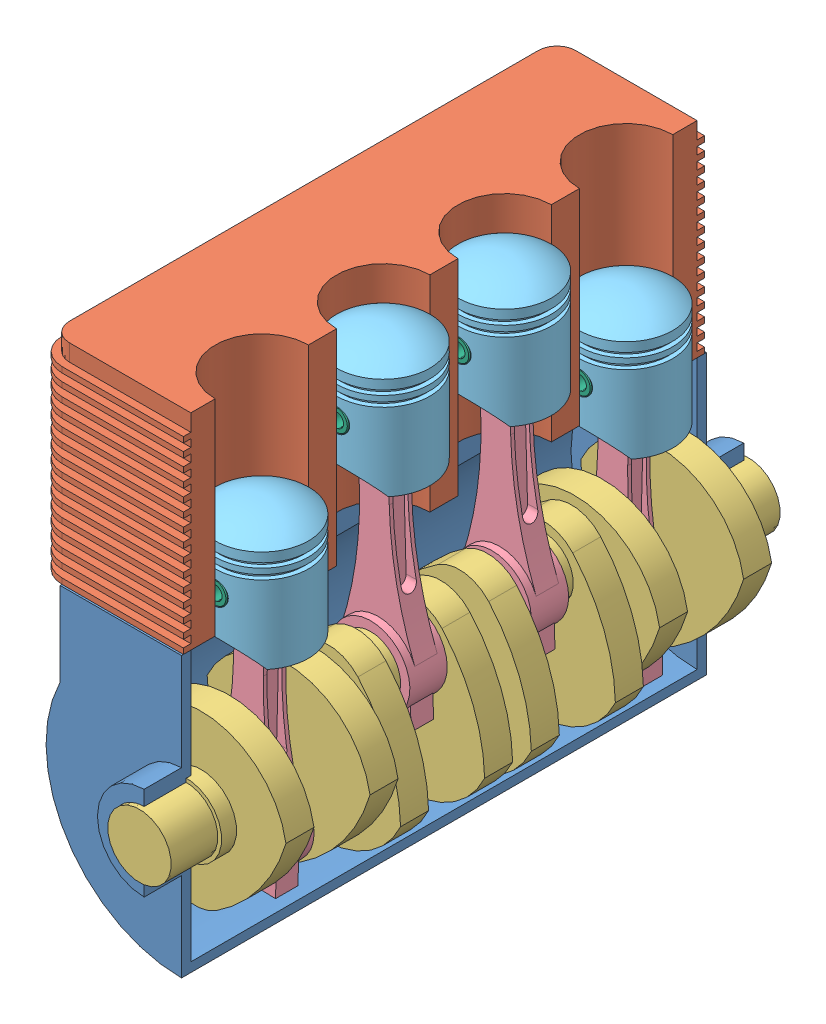
SolidWorks assembly Engine Block, configuration Default. Lengths in mm.
Overall size (128.7 259.5 326).
15 component instances, 6 part files, 29 mates.
Components (placement in the parent):
- Lower Block-1: Lower Block [Default] at (152.1459 172.8222 383.832) size (72.5 149.5 321)
- Upper Block-1: Upper Block [Default] at (114.6459 249.8222 243.332) x (0 0 -1) z (1 0 0) size (279 110 79)
- Crankshaft-1: Crankshaft [Default] at (152.1459 172.8222 381.332) x (0 0 -1) z (-0.991426 0.130668 0) size (326 92 88.14)
- Connecting Rod-1: Connecting Rod [Default] at (149.1155 150.0227 340.832) x (0.999681 -0.025253 0) z (0 0 1) size (42 160.15 20)
- Piston-1: Piston [Default] at (152.1459 239.4844 340.832) size (50 64.17 50)
- Piston Pin-1: Piston Pin [Default] at (152.1459 269.9844 340.832) size (12.5 12.5 50)
- Piston-2: Piston [Default] at (152.1459 239.4844 145.832) x (-1 0 0) z (0 0 -1) size (50 64.17 50)
- Piston Pin-2: Piston Pin [Default] at (152.1459 269.9844 145.832) x (-0.173648 0.984808 0) z (0 0 -1) size (12.5 12.5 50)
- Connecting Rod-2: Connecting Rod [Default] at (149.1155 150.0227 145.832) x (-0.999681 0.025253 0) z (0 0 -1) size (42 160.15 20)
- Connecting Rod-4: Connecting Rod [Default] at (155.4126 197.6078 275.832) x (0.999629 0.027222 0) z (0 0 1) size (42 160.15 20)
- Piston-4: Piston [Default] at (152.1459 287.0634 275.832) size (50 64.17 50)
- Piston Pin-4: Piston Pin [Default] at (152.1459 317.5634 275.832) size (12.5 12.5 50)
- Piston-7: Piston [Default] at (152.1459 287.0634 210.832) x (-1 0 0) z (0 0 -1) size (50 64.17 50)
- Connecting Rod-6: Connecting Rod [Default] at (155.4126 197.6078 210.832) x (-0.999629 -0.027222 0) z (0 0 -1) size (42 160.15 20)
- Piston Pin-6: Piston Pin [Default] at (152.1459 317.5634 210.832) x (-0.173648 0.984808 0) z (0 0 -1) size (12.5 12.5 50)
Mates (geometry in assembly coordinates):
- Coincident4: coincident: plane of Lower Block-1 through (152.1459 197.8222 378.832) normal (1 0 0); plane of Upper Block-1 through (152.1459 359.8222 378.832) normal (1 0 0)
- Coincident5: coincident: plane of Lower Block-1 through (152.1459 249.8222 378.832) normal (0 1 0); plane of Upper Block-1 through (87.1459 249.8222 368.832) normal (0 -1 0)
- Concentric1: concentric: cylinder of Lower Block-1 through (152.1459 172.8222 378.832) axis (0 0 1) radius 17; cylinder of Crankshaft-1 through (152.1459 172.8222 406.332) axis (0 0 -1) radius 17
- Concentric2: concentric: cylinder of Piston-1 through (152.1459 269.9844 315.832) axis (0 0 1) radius 6.25; cylinder of Piston Pin-1 through (152.1459 269.9844 365.832) axis (0 0 -1) radius 6.25
- Tangent1: tangent: cylinder of Piston-1 through (152.1459 301.9844 340.832) axis (0 1 0) radius 25; plane of Piston Pin-1 through (152.1459 269.9844 365.832) normal (0 0 1)
- Width2: width: plane of Piston-1 through (152.1459 269.9844 352.832) normal (0 0 -1); plane of Piston-1 through (152.1459 269.9844 328.832) normal (0 0 1); plane of Connecting Rod-1 through (149.1155 150.0227 350.832) normal (0 0 1); plane of Connecting Rod-1 through (149.1155 150.0227 330.832) normal (0 0 -1)
- Width4: width: plane of Lower Block-1 through (152.1459 172.8222 383.832) normal (0 0 1); plane of Lower Block-1 through (152.1459 172.8222 102.832) normal (0 0 -1); plane of Upper Block-1 through (152.1459 359.8222 107.832) normal (0 0 -1); plane of Upper Block-1 through (152.1459 359.8222 378.832) normal (0 0 1)
- Width5: width: plane of Crankshaft-1 through (152.1459 172.8222 406.332) normal (0 0 1); plane of Crankshaft-1 through (152.1459 172.8222 80.332) normal (0 0 -1); plane of Lower Block-1 through (152.1459 172.8222 82.832) normal (0 0 -1); plane of Lower Block-1 through (152.1459 172.8222 403.832) normal (0 0 1)
- Concentric5: concentric: cylinder of Connecting Rod-1 through (152.1459 269.9844 350.832) axis (0 0 -1) radius 6.25; cylinder of Piston Pin-1 through (152.1459 269.9844 365.832) axis (0 0 -1) radius 6.25
- Concentric6: concentric: cylinder of Crankshaft-1 through (149.1155 150.0227 343.332) axis (0 0 1) radius 16; cylinder of Connecting Rod-1 through (149.1155 150.0227 350.832) axis (0 0 -1) radius 16
- Concentric7: concentric: cylinder of Upper Block-1 through (152.1459 359.8222 340.832) axis (0 -1 0) radius 25; cylinder of Piston-1 through (152.1459 301.9844 340.832) axis (0 1 0) radius 25
- Concentric8: concentric: cylinder of Piston-2 through (152.1459 269.9844 170.832) axis (0 0 -1) radius 6.25; cylinder of Piston Pin-2 through (152.1459 269.9844 120.832) axis (0 0 1) radius 6.25
- Tangent4: tangent: cylinder of Piston-2 through (152.1459 301.9844 145.832) axis (0 1 0) radius 25; plane of Piston Pin-2 through (152.1459 269.9844 120.832) normal (0 0 -1)
- Width6: width: plane of Piston-2 through (152.1459 269.9844 133.832) normal (0 0 1); plane of Piston-2 through (152.1459 269.9844 157.832) normal (0 0 -1); plane of Connecting Rod-2 through (149.1155 150.0227 135.832) normal (0 0 -1); plane of Connecting Rod-2 through (149.1155 150.0227 155.832) normal (0 0 1)
- Concentric9: concentric: cylinder of Piston Pin-2 through (152.1459 269.9844 120.832) axis (0 0 1) radius 6.25; cylinder of Connecting Rod-2 through (152.1459 269.9844 135.832) axis (0 0 1) radius 6.25
- Concentric10: concentric: cylinder of Crankshaft-1 through (149.1155 150.0227 143.332) axis (0 0 -1) radius 16; cylinder of Connecting Rod-2 through (149.1155 150.0227 135.832) axis (0 0 1) radius 16
- Concentric11: concentric: cylinder of Upper Block-1 through (152.1459 359.8222 145.832) axis (0 -1 0) radius 25; cylinder of Piston-2 through (152.1459 301.9844 145.832) axis (0 1 0) radius 25
- Concentric14: concentric: cylinder of Piston-4 through (152.1459 317.5634 250.832) axis (0 0 1) radius 6.25; cylinder of Piston Pin-4 through (152.1459 317.5634 300.832) axis (0 0 -1) radius 6.25
- Tangent6: tangent: cylinder of Piston-4 through (152.1459 349.5634 275.832) axis (0 1 0) radius 25; plane of Piston Pin-4 through (152.1459 317.5634 300.832) normal (0 0 1)
- Concentric15: concentric: cylinder of Connecting Rod-4 through (152.1459 317.5634 285.832) axis (0 0 -1) radius 6.25; cylinder of Piston Pin-4 through (152.1459 317.5634 300.832) axis (0 0 -1) radius 6.25
- Width8: width: plane of Piston-4 through (152.1459 317.5634 287.832) normal (0 0 -1); plane of Piston-4 through (152.1459 317.5634 263.832) normal (0 0 1); plane of Connecting Rod-4 through (155.4126 197.6078 285.832) normal (0 0 1); plane of Connecting Rod-4 through (155.4126 197.6078 265.832) normal (0 0 -1)
- Concentric16: concentric: cylinder of Crankshaft-1 through (155.4126 197.6078 263.332) axis (0 0 1) radius 16; cylinder of Connecting Rod-4 through (155.4126 197.6078 285.832) axis (0 0 -1) radius 16
- Concentric17: concentric: cylinder of Upper Block-1 through (152.1459 359.8222 275.832) axis (0 -1 0) radius 25; cylinder of Piston-4 through (152.1459 349.5634 275.832) axis (0 1 0) radius 25
- Concentric22: concentric: cylinder of Piston-7 through (152.1459 317.5634 235.832) axis (0 0 -1) radius 6.25; cylinder of Piston Pin-6 through (152.1459 317.5634 185.832) axis (0 0 1) radius 6.25
- Tangent8: tangent: cylinder of Piston-7 through (152.1459 349.5634 210.832) axis (0 1 0) radius 25; plane of Piston Pin-6 through (152.1459 317.5634 185.832) normal (0 0 -1)
- Concentric23: concentric: cylinder of Connecting Rod-6 through (152.1459 317.5634 200.832) axis (0 0 1) radius 6.25; cylinder of Piston Pin-6 through (152.1459 317.5634 185.832) axis (0 0 1) radius 6.25
- Width10: width: plane of Piston-7 through (152.1459 317.5634 198.832) normal (0 0 1); plane of Piston-7 through (152.1459 317.5634 222.832) normal (0 0 -1); plane of Connecting Rod-6 through (155.4126 197.6078 200.832) normal (0 0 -1); plane of Connecting Rod-6 through (155.4126 197.6078 220.832) normal (0 0 1)
- Concentric24: concentric: cylinder of Crankshaft-1 through (155.4126 197.6078 223.332) axis (0 0 -1) radius 16; cylinder of Connecting Rod-6 through (155.4126 197.6078 200.832) axis (0 0 1) radius 16
- Concentric25: concentric: cylinder of Upper Block-1 through (152.1459 359.8222 210.832) axis (0 -1 0) radius 25; cylinder of Piston-7 through (152.1459 349.5634 210.832) axis (0 1 0) radius 25
